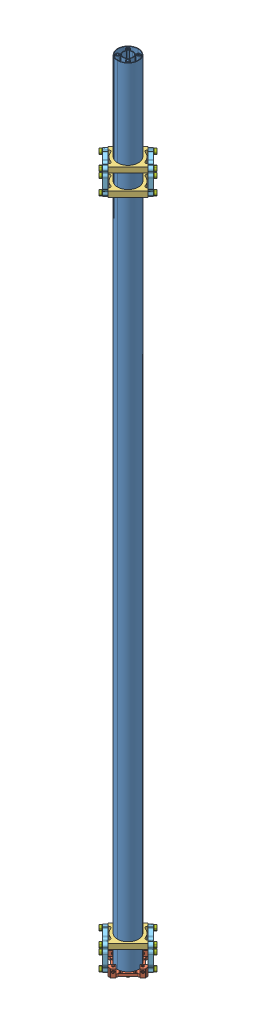
SolidWorks assembly bar joint, configuration 默认. Lengths in mm.
Overall size (78.16 1207.96 78.16).
50 component instances, 7 part files, 42 mates.
Components (placement in the parent):
- 4103-0032-1200-1: 4103-0032-1200 [Default] at (-382.4496 -218.103 848.4527) size (31.95 1200 31.95)
- 1201-0043-0002-1: 1201-0043-0002 [Default] at (-382.4496 -222.053 848.4527) x (0.707107 0 -0.707107) z (0.707107 0 0.707107) size (43.01 12.01 43.01)
- 1401-0043-0032 assembly-1: 1401-0043-0032 assembly [Default] at (-379.8973 -194.1729 852.1265) x (0.707107 0 -0.707107) z (0.707107 0 0.707107) size (43.01 8.04 47.02)
  - 1401-0043-0032 assembly.STEP-1: 1401-0043-0032 assembly.STEP [Default] at origin size (43.01 8.04 47.02)
    - 1401-0043-0032.STEP-1: 1401-0043-0032.STEP [Default] at (0.7931 12.12 -4.4026) size (43.01 8 46.5)
    - 2800-0004-0014_90128A207.STEP-1: 2800-0004-0014_90128A207.STEP [Default] at (7.7931 12.12 -28.4026) x (0 0.161804 -0.986823) z (1 0 0) size (7 7 18.01)
- 1603-0032-0032 assembly-1: 1603-0032-0032 assembly [Default] at (-414.7994 -229.5005 871.284) x (0 -1 0) z (0.707107 0 0.707107) size (55.53 6 55.53)
  - 1603-0032-0032 assembly.STEP-1: 1603-0032-0032 assembly.STEP [Default] at origin size (55.53 6 55.53)
    - 1603-0032-0032.STEP-1: 1603-0032-0032.STEP [Default] at (-31.4475 11.5189 6.7305) size (43 6 43)
    - 1601-0039-00032.STEP-1: 1601-0039-00032.STEP [Default] at (-31.4475 15.0189 6.7305) x (0.473716 0 0.880678) z (-0.880678 0 0.473716) size (41 5 41)
- 1603-0032-0032 assembly-2: 1603-0032-0032 assembly [Default] at (-353.1552 -204.7835 863.6318) x (0.707107 0 0.707107) z (0 1 0) size (55.53 6 55.53)
  - 1603-0032-0032 assembly.STEP-1: 1603-0032-0032 assembly.STEP [Default] at origin size (55.53 6 55.53)
    - 1603-0032-0032.STEP-1: 1603-0032-0032.STEP [Default] at (-31.4475 11.5189 6.7305) size (43 6 43)
    - 1601-0039-00032.STEP-1: 1601-0039-00032.STEP [Default] at (-31.4475 15.0189 6.7305) x (0.473716 0 0.880678) z (-0.880678 0 0.473716) size (41 5 41)
- 1603-0032-0032 assembly-3: 1603-0032-0032 assembly [Default] at (-353.1552 820.1665 863.6318) x (0.707107 0 0.707107) z (0 1 0) size (55.53 6 55.53)
  - 1603-0032-0032 assembly.STEP-1: 1603-0032-0032 assembly.STEP [Default] at origin size (55.53 6 55.53)
    - 1603-0032-0032.STEP-1: 1603-0032-0032.STEP [Default] at (-31.4475 11.5189 6.7305) size (43 6 43)
    - 1601-0039-00032.STEP-1: 1601-0039-00032.STEP [Default] at (-31.4475 15.0189 6.7305) x (0.473716 0 0.880678) z (-0.880678 0 0.473716) size (41 5 41)
- 1603-0032-0032 assembly-4: 1603-0032-0032 assembly [Default] at (-414.7994 795.4495 871.284) x (0 -1 0) z (0.707107 0 0.707107) size (55.53 6 55.53)
  - 1603-0032-0032 assembly.STEP-1: 1603-0032-0032 assembly.STEP [Default] at origin size (55.53 6 55.53)
    - 1603-0032-0032.STEP-1: 1603-0032-0032.STEP [Default] at (-31.4475 11.5189 6.7305) size (43 6 43)
    - 1601-0039-00032.STEP-1: 1601-0039-00032.STEP [Default] at (-31.4475 15.0189 6.7305) x (0.473716 0 0.880678) z (-0.880678 0 0.473716) size (41 5 41)
- 1401-0043-0032 assembly-2: 1401-0043-0032 assembly [Default] at (-379.8973 830.7771 852.1265) x (0.707107 0 -0.707107) z (0.707107 0 0.707107) size (43.01 8.04 47.02)
  - 1401-0043-0032 assembly.STEP-1: 1401-0043-0032 assembly.STEP [Default] at origin size (43.01 8.04 47.02)
    - 1401-0043-0032.STEP-1: 1401-0043-0032.STEP [Default] at (0.7931 12.12 -4.4026) size (43.01 8 46.5)
    - 2800-0004-0014_90128A207.STEP-1: 2800-0004-0014_90128A207.STEP [Default] at (7.7931 12.12 -28.4026) x (0 0.161804 -0.986823) z (1 0 0) size (7 7 18.01)
- 1401-0043-0032 assembly-3: 1401-0043-0032 assembly [Default] at (-379.8973 798.7771 852.1265) x (0.707107 0 -0.707107) z (0.707107 0 0.707107) size (43.01 8.04 47.02)
  - 1401-0043-0032 assembly.STEP-1: 1401-0043-0032 assembly.STEP [Default] at origin size (43.01 8.04 47.02)
    - 1401-0043-0032.STEP-1: 1401-0043-0032.STEP [Default] at (0.7931 12.12 -4.4026) size (43.01 8 46.5)
    - 2800-0004-0014_90128A207.STEP-1: 2800-0004-0014_90128A207.STEP [Default] at (7.7931 12.12 -28.4026) x (0 0.161804 -0.986823) z (1 0 0) size (7 7 18.01)
- 2800-0004-0010-2: 2800-0004-0010 [Default] at (-390.4496 -212.053 840.4527) x (0.991218 0 0.132238) z (0 1 0) size (7 7 14.01)
- 2800-0004-0010-3: 2800-0004-0010 [Default] at (-374.4496 -212.053 840.4527) x (0.992272 0 0.124084) z (0 1 0) size (7 7 14.01)
- 2800-0004-0010-4: 2800-0004-0010 [Default] at (-374.4496 -212.053 856.4527) x (0.986904 0 0.161312) z (0 1 0) size (7 7 14.01)
- 2800-0004-0010-5: 2800-0004-0010 [Default] at (-390.4496 -212.053 856.4527) x (0.988539 0 0.150963) z (0 1 0) size (7 7 14.01)
- 2800-0004-0010-6: 2800-0004-0010 [Default] at (-381.389 -214.053 824.7646) x (0.574624 0.582765 0.574624) z (-0.707107 0 0.707107) size (7 7 14.01)
- 2800-0004-0010-7: 2800-0004-0010 [Default] at (-381.389 -182.053 824.7646) x (-0.675476 -0.295745 -0.675476) z (-0.707107 0 0.707107) size (7 7 14.01)
- 2800-0004-0010-8: 2800-0004-0010 [Default] at (-358.7616 -182.053 847.392) x (-0.524949 -0.669968 -0.524949) z (-0.707107 0 0.707107) size (7 7 14.01)
- 2800-0004-0010-9: 2800-0004-0010 [Default] at (-358.7616 -214.053 847.392) x (-0.400877 -0.823769 -0.400877) z (-0.707107 0 0.707107) size (7 7 14.01)
- 2800-0004-0010-10: 2800-0004-0010 [Default] at (-406.1377 -214.053 849.5133) x (0.574624 0.582765 0.574624) z (0.707107 0 -0.707107) size (7 7 14.01)
- 2800-0004-0010-11: 2800-0004-0010 [Default] at (-383.5103 -214.053 872.1407) x (-0.400877 -0.823769 -0.400877) z (0.707107 0 -0.707107) size (7 7 14.01)
- 2800-0004-0010-12: 2800-0004-0010 [Default] at (-383.5103 -182.053 872.1407) x (-0.524949 -0.669968 -0.524949) z (0.707107 0 -0.707107) size (7 7 14.01)
- 2800-0004-0010-13: 2800-0004-0010 [Default] at (-406.1377 -182.053 849.5133) x (-0.675476 -0.295745 -0.675476) z (0.707107 0 -0.707107) size (7 7 14.01)
- 2800-0004-0010-14: 2800-0004-0010 [Default] at (-381.389 842.897 824.7646) x (-0.706758 -0.031427 -0.706758) z (-0.707107 0 0.707107) size (7 7 14.01)
- 2800-0004-0010-15: 2800-0004-0010 [Default] at (-381.389 810.897 824.7646) x (-0.69677 -0.170361 -0.69677) z (-0.707107 0 0.707107) size (7 7 14.01)
- 2800-0004-0010-16: 2800-0004-0010 [Default] at (-358.7616 810.897 847.392) x (-0.333195 -0.882021 -0.333195) z (-0.707107 0 0.707107) size (7 7 14.01)
- 2800-0004-0010-17: 2800-0004-0010 [Default] at (-358.7616 842.897 847.392) x (-0.462106 -0.756912 -0.462106) z (-0.707107 0 0.707107) size (7 7 14.01)
- 2800-0004-0010-18: 2800-0004-0010 [Default] at (-406.1377 842.897 849.5133) x (-0.706758 -0.031427 -0.706758) z (0.707107 0 -0.707107) size (7 7 14.01)
- 2800-0004-0010-19: 2800-0004-0010 [Default] at (-406.1377 810.897 849.5133) x (-0.69677 -0.170361 -0.69677) z (0.707107 0 -0.707107) size (7 7 14.01)
- 2800-0004-0010-20: 2800-0004-0010 [Default] at (-383.5103 810.897 872.1407) x (-0.333195 -0.882021 -0.333195) z (0.707107 0 -0.707107) size (7 7 14.01)
- 2800-0004-0010-21: 2800-0004-0010 [Default] at (-383.5103 842.897 872.1407) x (-0.462106 -0.756912 -0.462106) z (0.707107 0 -0.707107) size (7 7 14.01)
Mates (geometry in assembly coordinates):
- 同心1: concentric anti-aligned: circle of 4103-0032-1200-1; circle of 1201-0043-0002-1
- 重合1: coincident anti-aligned: cone of 4103-0032-1200-1 through (-390.4496 -218.103 856.4527) axis (0 1 0); circle of 1201-0043-0002-1
- 同心4: concentric anti-aligned: cylinder of 4103-0032-1200-1 through (-382.4496 981.897 848.4527) axis (0 -1 0) radius 15.975; cylinder of 1401-0043-0032 assembly-1/1401-0043-0032 assembly.STEP-1/1401-0043-0032.STEP-1 through (-382.4496 -186.053 848.4527) axis (0 1 0) radius 16
- 重合2: coincident anti-aligned: circle of 1401-0043-0032 assembly-1/1401-0043-0032 assembly.STEP-1/1401-0043-0032.STEP-1; circle of 1603-0032-0032 assembly-1/1603-0032-0032 assembly.STEP-1/1603-0032-0032.STEP-1
- 重合3: coincident anti-aligned: circle of 1201-0043-0002-1; circle of 1603-0032-0032 assembly-1/1603-0032-0032 assembly.STEP-1/1603-0032-0032.STEP-1
- 重合4: coincident anti-aligned: circle of 1401-0043-0032 assembly-1/1401-0043-0032 assembly.STEP-1/1401-0043-0032.STEP-1; circle of 1603-0032-0032 assembly-2/1603-0032-0032 assembly.STEP-1/1603-0032-0032.STEP-1
- 重合5: coincident anti-aligned: circle of 1201-0043-0002-1; circle of 1603-0032-0032 assembly-2/1603-0032-0032 assembly.STEP-1/1603-0032-0032.STEP-1
- 同心12: concentric anti-aligned: circle of 1201-0043-0002-1; circle of 1603-0032-0032 assembly-1/1603-0032-0032 assembly.STEP-1/1603-0032-0032.STEP-1
- 同心14: concentric aligned: circle of 1401-0043-0032 assembly-1/1401-0043-0032 assembly.STEP-1/1401-0043-0032.STEP-1; circle of 1603-0032-0032 assembly-2/1603-0032-0032 assembly.STEP-1/1603-0032-0032.STEP-1
- 重合8: coincident anti-aligned: circle of 1603-0032-0032 assembly-4/1603-0032-0032 assembly.STEP-1/1603-0032-0032.STEP-1; circle of 1401-0043-0032 assembly-2/1401-0043-0032 assembly.STEP-1/1401-0043-0032.STEP-1
- 重合9: coincident anti-aligned: circle of 1603-0032-0032 assembly-3/1603-0032-0032 assembly.STEP-1/1603-0032-0032.STEP-1; circle of 1401-0043-0032 assembly-2/1401-0043-0032 assembly.STEP-1/1401-0043-0032.STEP-1
- 同心15: concentric aligned: circle of 1603-0032-0032 assembly-3/1603-0032-0032 assembly.STEP-1/1603-0032-0032.STEP-1; circle of 1401-0043-0032 assembly-2/1401-0043-0032 assembly.STEP-1/1401-0043-0032.STEP-1
- 同心16: concentric anti-aligned: cylinder of 4103-0032-1200-1 through (-382.4496 981.897 848.4527) axis (0 -1 0) radius 15.975; cylinder of 1401-0043-0032 assembly-2/1401-0043-0032 assembly.STEP-1/1401-0043-0032.STEP-1 through (-382.4496 838.897 848.4527) axis (0 1 0) radius 16
- 距离1: distance = 135 mm aligned: plane of 1401-0043-0032 assembly-2/1401-0043-0032 assembly.STEP-1/1401-0043-0032.STEP-1 through (-382.4496 846.897 848.4527) normal (0 1 0); plane of 4103-0032-1200-1 through (-382.4496 981.897 848.4527) normal (0 1 0)
- 同心17: concentric anti-aligned: cylinder of 4103-0032-1200-1 through (-382.4496 981.897 848.4527) axis (0 -1 0) radius 15.975; cylinder of 1401-0043-0032 assembly-3/1401-0043-0032 assembly.STEP-1/1401-0043-0032.STEP-1 through (-382.4496 806.897 848.4527) axis (0 1 0) radius 16
- 重合11: coincident anti-aligned: circle of 1603-0032-0032 assembly-3/1603-0032-0032 assembly.STEP-1/1603-0032-0032.STEP-1; circle of 1401-0043-0032 assembly-3/1401-0043-0032 assembly.STEP-1/1401-0043-0032.STEP-1
- 重合12: coincident anti-aligned: circle of 1603-0032-0032 assembly-4/1603-0032-0032 assembly.STEP-1/1603-0032-0032.STEP-1; circle of 1401-0043-0032 assembly-3/1401-0043-0032 assembly.STEP-1/1401-0043-0032.STEP-1
- 重合13: coincident aligned: plane of 1603-0032-0032 assembly-1/1603-0032-0032 assembly.STEP-1/1603-0032-0032.STEP-1 through (-401.8951 -198.053 867.8981) normal (-0.707107 0 0.707107); plane of 1603-0032-0032 assembly-4/1603-0032-0032 assembly.STEP-1/1603-0032-0032.STEP-1 through (-401.8951 826.897 867.8981) normal (-0.707107 0 0.707107)
- 同心18: concentric aligned: circle of 1201-0043-0002-1; circle of 2800-0004-0010-5
- 重合14: coincident anti-aligned: plane of 1201-0043-0002-1 through (-382.4496 -222.053 848.4527) normal (0 -1 0); plane of 2800-0004-0010-5 through (-390.4496 -222.053 856.4527) normal (0 1 0)
- 同心19: concentric aligned: circle of 1201-0043-0002-1; circle of 2800-0004-0010-3
- 重合15: coincident anti-aligned: plane of 1201-0043-0002-1 through (-382.4496 -222.053 848.4527) normal (0 -1 0); plane of 2800-0004-0010-3 through (-374.4496 -222.053 840.4527) normal (0 1 0)
- 同心20: concentric aligned: circle of 1201-0043-0002-1; circle of 2800-0004-0010-2
- 重合16: coincident anti-aligned: plane of 1201-0043-0002-1 through (-382.4496 -222.053 848.4527) normal (0 -1 0); plane of 2800-0004-0010-2 through (-390.4496 -222.053 840.4527) normal (0 1 0)
- 同心21: concentric aligned: circle of 1201-0043-0002-1; circle of 2800-0004-0010-4
- 重合17: coincident anti-aligned: plane of 1201-0043-0002-1 through (-382.4496 -222.053 848.4527) normal (0 -1 0); plane of 2800-0004-0010-4 through (-374.4496 -222.053 856.4527) normal (0 1 0)
- 同心22: concentric anti-aligned: circle of 1603-0032-0032 assembly-2/1603-0032-0032 assembly.STEP-1/1603-0032-0032.STEP-1; circle of 2800-0004-0010-6
- 重合18: coincident anti-aligned: plane of 1603-0032-0032 assembly-2/1603-0032-0032 assembly.STEP-1/1603-0032-0032.STEP-1 through (-363.0042 -198.053 829.0072) normal (0.707107 0 -0.707107); plane of 2800-0004-0010-6 through (-374.3179 -214.053 817.6935) normal (-0.707107 0 0.707107)
- 同心24: concentric aligned: circle of 1603-0032-0032 assembly-2/1603-0032-0032 assembly.STEP-1/1603-0032-0032.STEP-1; circle of 2800-0004-0010-7
- 重合19: coincident anti-aligned: plane of 1603-0032-0032 assembly-2/1603-0032-0032 assembly.STEP-1/1603-0032-0032.STEP-1 through (-363.0042 -198.053 829.0072) normal (0.707107 0 -0.707107); plane of 2800-0004-0010-7 through (-374.3179 -182.053 817.6935) normal (-0.707107 0 0.707107)
- 同心25: concentric aligned: circle of 1603-0032-0032 assembly-2/1603-0032-0032 assembly.STEP-1/1603-0032-0032.STEP-1; circle of 2800-0004-0010-8
- 重合20: coincident anti-aligned: plane of 1603-0032-0032 assembly-2/1603-0032-0032 assembly.STEP-1/1603-0032-0032.STEP-1 through (-363.0042 -198.053 829.0072) normal (0.707107 0 -0.707107); plane of 2800-0004-0010-8 through (-351.6905 -182.053 840.3209) normal (-0.707107 0 0.707107)
- 同心26: concentric aligned: circle of 1603-0032-0032 assembly-2/1603-0032-0032 assembly.STEP-1/1603-0032-0032.STEP-1; circle of 2800-0004-0010-9
- 重合21: coincident anti-aligned: plane of 1603-0032-0032 assembly-2/1603-0032-0032 assembly.STEP-1/1603-0032-0032.STEP-1 through (-363.0042 -198.053 829.0072) normal (0.707107 0 -0.707107); plane of 2800-0004-0010-9 through (-351.6905 -214.053 840.3209) normal (-0.707107 0 0.707107)
- 同心27: concentric aligned: circle of 1603-0032-0032 assembly-3/1603-0032-0032 assembly.STEP-1/1603-0032-0032.STEP-1; circle of 2800-0004-0010-14
- 重合22: coincident anti-aligned: plane of 1603-0032-0032 assembly-3/1603-0032-0032 assembly.STEP-1/1603-0032-0032.STEP-1 through (-363.0042 826.897 829.0072) normal (0.707107 0 -0.707107); plane of 2800-0004-0010-14 through (-374.3179 842.897 817.6935) normal (-0.707107 0 0.707107)
- 同心28: concentric aligned: circle of 1603-0032-0032 assembly-3/1603-0032-0032 assembly.STEP-1/1603-0032-0032.STEP-1; circle of 2800-0004-0010-15
- 重合23: coincident anti-aligned: plane of 1603-0032-0032 assembly-3/1603-0032-0032 assembly.STEP-1/1603-0032-0032.STEP-1 through (-363.0042 826.897 829.0072) normal (0.707107 0 -0.707107); plane of 2800-0004-0010-15 through (-374.3179 810.897 817.6935) normal (-0.707107 0 0.707107)
- 同心29: concentric aligned: circle of 1603-0032-0032 assembly-3/1603-0032-0032 assembly.STEP-1/1603-0032-0032.STEP-1; circle of 2800-0004-0010-16
- 重合25: coincident anti-aligned: plane of 1603-0032-0032 assembly-3/1603-0032-0032 assembly.STEP-1/1603-0032-0032.STEP-1 through (-363.0042 826.897 829.0072) normal (0.707107 0 -0.707107); plane of 2800-0004-0010-16 through (-351.6905 810.897 840.3209) normal (-0.707107 0 0.707107)
- 同心30: concentric aligned: circle of 1603-0032-0032 assembly-3/1603-0032-0032 assembly.STEP-1/1603-0032-0032.STEP-1; circle of 2800-0004-0010-17
- 重合26: coincident anti-aligned: plane of 1603-0032-0032 assembly-3/1603-0032-0032 assembly.STEP-1/1603-0032-0032.STEP-1 through (-363.0042 826.897 829.0072) normal (0.707107 0 -0.707107); plane of 2800-0004-0010-17 through (-351.6905 842.897 840.3209) normal (-0.707107 0 0.707107)
